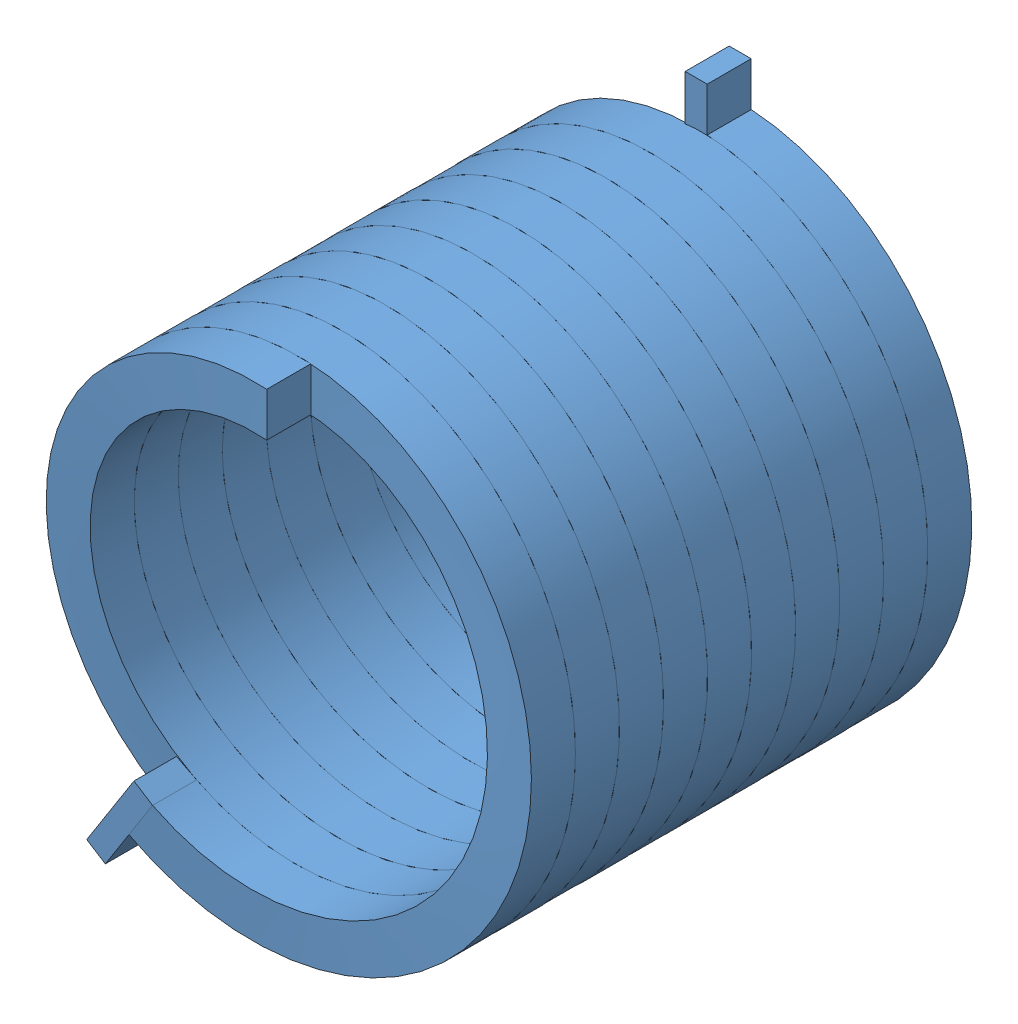
SolidWorks assembly Assemblage1, configuration Défaut. Lengths in mm.
Overall size (78.6 80.14 55.9).
2 component instances, 1 part files, 4 mates.
Components (placement in the parent):
- Pièce2^Assemblage1-1: Pièce2^Assemblage1 [Défaut] at origin size (55 60 55) (virtual)
- Pièce2^Assemblage1-2: Pièce2^Assemblage1 [Défaut] at (0 0 50.9008) x (0.844055 -0.536257 0) z (0 0 -1) size (55 60 55) (virtual)
Mates (geometry in assembly coordinates):
- Coïncidente1: coincident: plane of Pièce2^Assemblage1-1 through (0 25 51.25) normal (1 0 0); plane of ?
- Coïncidente2: coincident: line of Pièce2^Assemblage1-1 through (0 0 -3.875) axis (0 0 1); line of ? through (0 0 98.875) axis (0 0 -1)
- Distance1: distance = 2.5 mm: line of Pièce2^Assemblage1-1 through (0 26.25 48.75) axis (0 -1 0); line of ? through (0 26.25 46.25) axis (0 -1 0)
- Hélicoïdale1: screw = 10 mm anti-aligned: line of Pièce2^Assemblage1-1 through (0 0 -3.875) axis (0 0 1); line of Pièce2^Assemblage1-2 through (0 0 54.7758) axis (0 0 -1)
